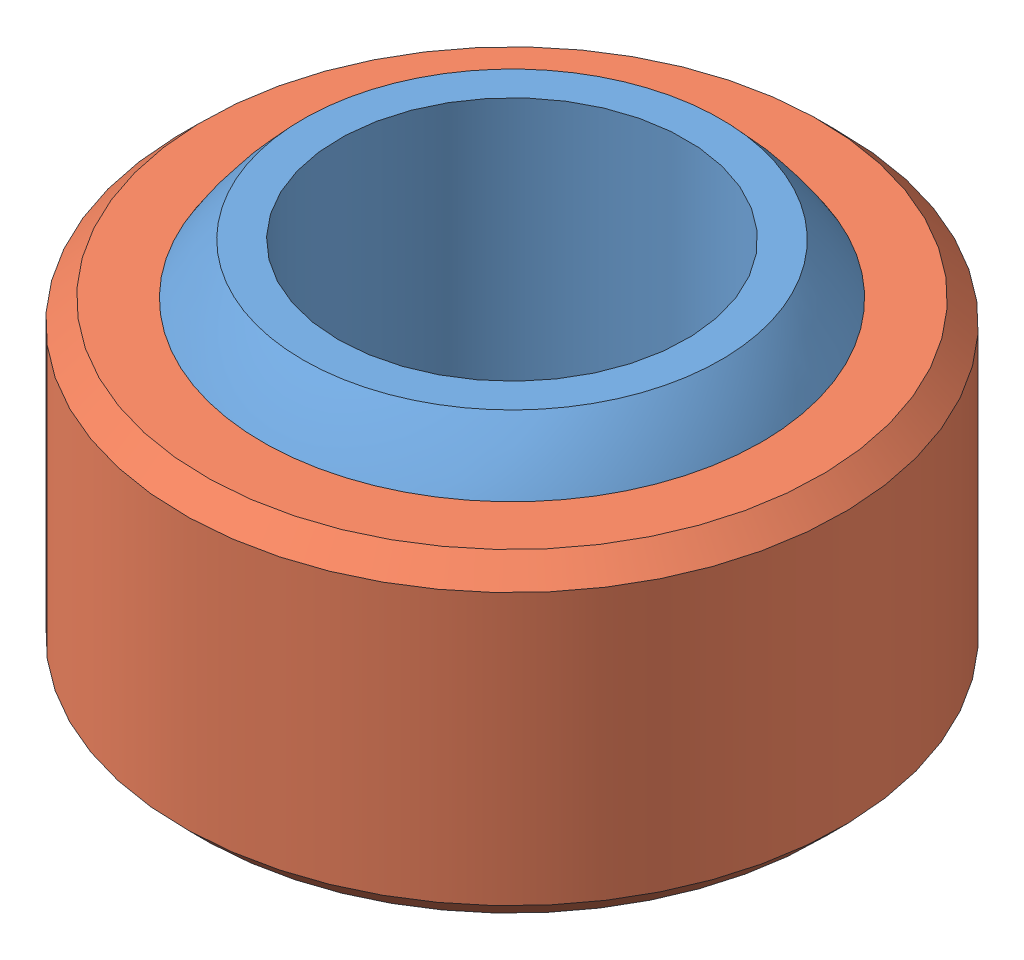
SolidWorks assembly BearingSpherical625, configuration Default. Lengths in mm.
Overall size (30.79 22.58 32.6).
2 component instances, 2 part files, 2 mates.
Components (placement in the parent):
- SphericalBearingBall625-1: SphericalBearingBall625 [Default] x (1 0 0) z (0 -1 0) size (26.97 32.6 22.58)
- SphericalBeaingRace625-1: SphericalBeaingRace625 [Default] x (0.999776 0 -0.021151) z (0 -1 0) size (30.16 30.16 14.4)
Mates (geometry in assembly coordinates):
- Coincident1: coincident: plane of assembly through (0 0 0) normal (0 1 0); plane of SphericalBearingBall625-1 through (0 0 0) normal (0 -1 0); plane of assembly
- Concentric1: concentric: sphere of assembly; sphere of assembly; sphere of SphericalBearingBall625-1; sphere of SphericalBeaingRace625-1
